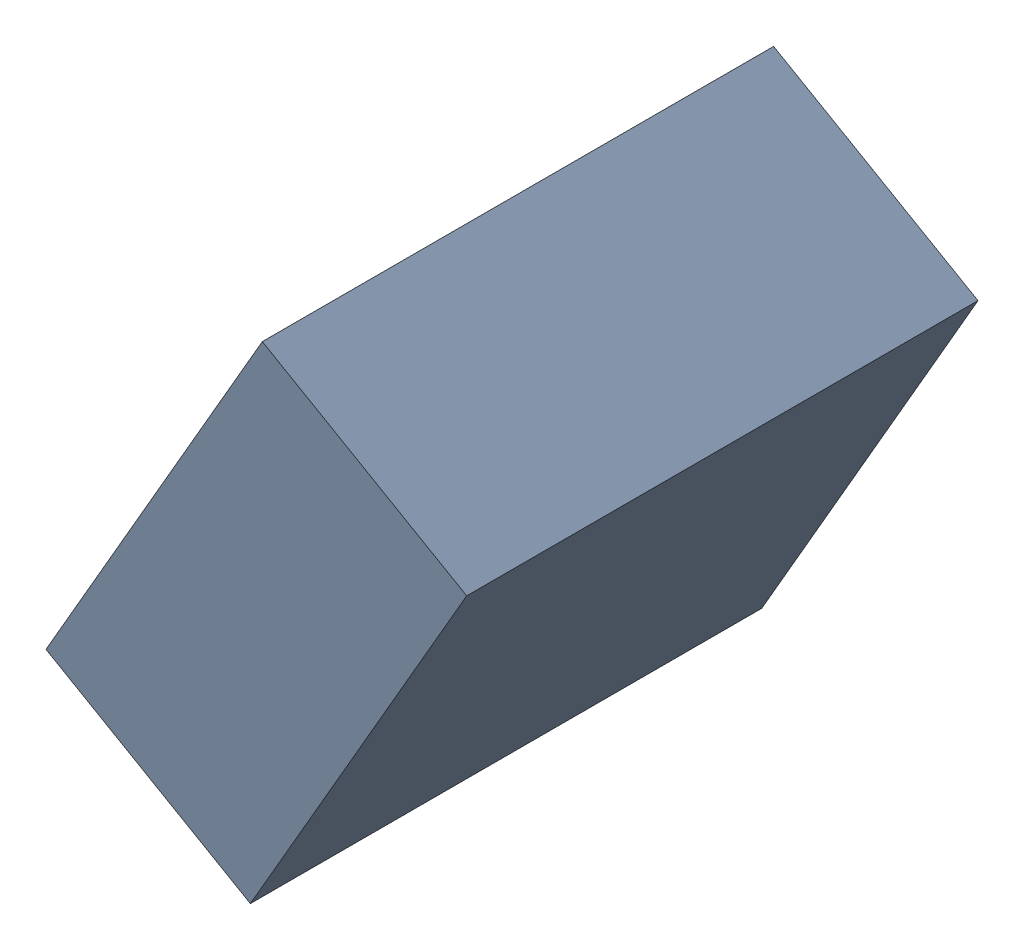
SolidWorks assembly C29_TDA6, configuration Standard. Lengths in mm.
Overall size (1.07 1.25 1.3).
2 component instances, 1 part files, 0 mates.
Components (placement in the parent):
- 885543328-1: 885543328 [Standard] at (-49.3371 30.7379 0) size (1.07 1.25 1.3)
  - Extruded_26-1: Extruded_26 [Standard] at origin size (1.07 1.25 1.3)
